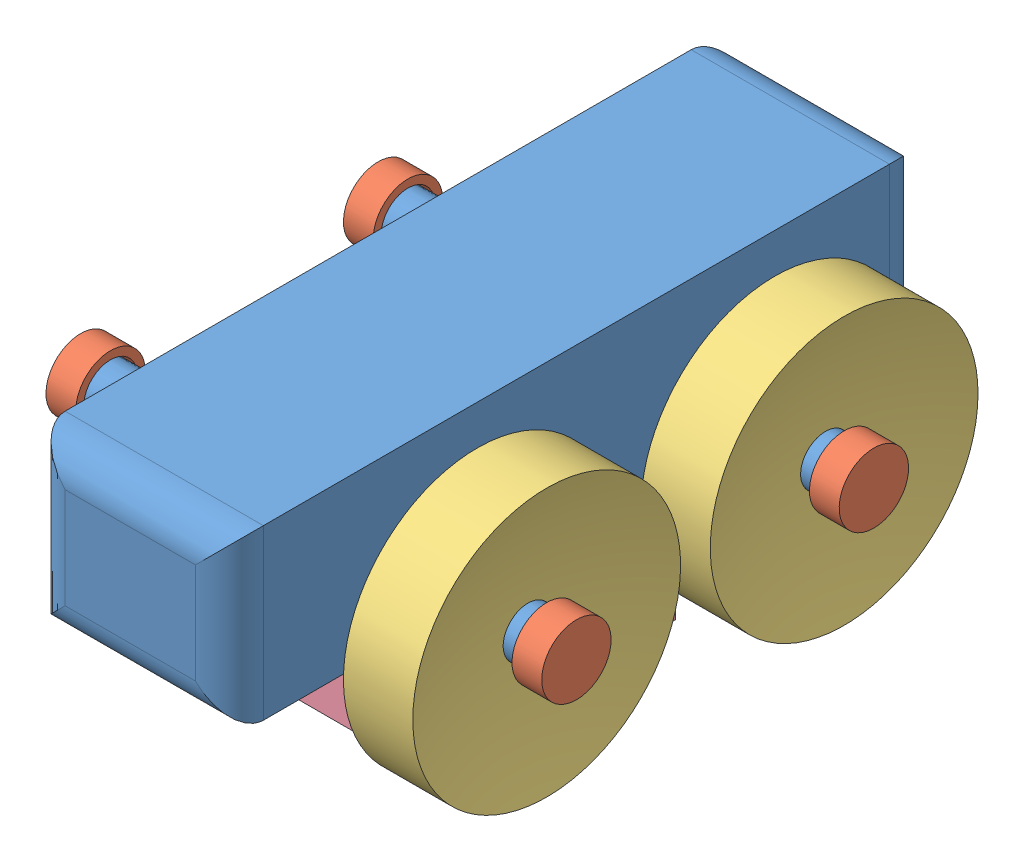
SolidWorks assembly FullCar, configuration Default. Lengths in mm.
Overall size (25 18.99 35).
10 component instances, 4 part files, 11 mates.
Components (placement in the parent):
- Carriage-1: Carriage [Default] at origin size (24.16 8.5 35)
- LockWheels-1: LockWheels [Default] at (12.5 0 7.5) x (0 0.86398 0.503526) z (0 -0.503526 0.86398) size (3.5 7.63 3.5)
- LockWheels-2: LockWheels [Default] at (12.5 0 -7.5) x (0 -0.86398 0.503526) z (0 -0.503526 -0.86398) size (3.5 7.63 3.5)
- LockWheels-3: LockWheels [Default] at (-12.5 0 7.5) x (0 -0.86398 -0.503526) z (0 -0.503526 0.86398) size (3.5 7.63 3.5)
- LockWheels-4: LockWheels [Default] at (-12.5 0 -7.5) x (0 0.86398 -0.503526) z (0 -0.503526 -0.86398) size (3.5 7.63 3.5)
- WheelCarriage-1: WheelCarriage [Default] at (9.25 0 7.5) x (0 -0.862763 -0.505608) z (1 0 0) size (13.5 13.5 3.5)
- WheelCarriage-2: WheelCarriage [Default] at (9.25 0 -7.5) x (0 -0.862763 0.505608) z (-1 0 0) size (13.5 13.5 3.5)
- WheelCarriage-3: WheelCarriage [Default] at (-9.25 0 7.5) x (0 -0.862763 -0.505608) z (1 0 0) size (13.5 13.5 3.5) (hidden)
- WheelCarriage-4: WheelCarriage [Default] at (-9.25 0 -7.5) x (0 -0.862763 0.505608) z (-1 0 0) size (13.5 13.5 3.5) (hidden)
- Support-1: Support [Default] at (0 -7.5 0) x (0 0 1) z (-1 0 0) size (13 7.5 7)
Mates (geometry in assembly coordinates):
- Coincident1: coincident aligned: axis of Carriage-1 through (6.25 0 7.5) axis (1 0 0); line of LockWheels-1 through (5.1 0 7.5) axis (1 0 0)
- Screw1: screw = 1 mm aligned: line of Carriage-1 through (6.25 0 7.5) axis (1 0 0); line of LockWheels-1 through (5.1 0 7.5) axis (1 0 0)
- LimitDistance2: limit distance = 7 mm anti-aligned: plane of Carriage-1 through (5 -1.25 -15.7859) normal (1 0 0); plane of LockWheels-1 through (12 0 7.5) normal (-1 0 0)
- Coincident5: coincident aligned: plane of Carriage-1 through (0 0 0) normal (0 0 1)
- Coincident6: coincident aligned: plane of Carriage-1 through (0 0 0) normal (0 1 0)
- Coincident7: coincident aligned: plane of Carriage-1 through (0 0 0) normal (1 0 0)
- Coincident8: coincident anti-aligned: line of Carriage-1 through (6.25 0 7.5) axis (1 0 0); line of WheelCarriage-1 through (11 0 7.5) axis (-1 0 0)
- LimitDistance3: limit distance = 4.25 mm aligned: plane of Carriage-1 through (5 -1.25 -15.7859) normal (1 0 0); plane of WheelCarriage-1 through (9.25 0 7.5) normal (1 0 0)
- Coincident9: coincident anti-aligned: plane of Carriage-1 through (-3.2859 -2.25 -15.7859) normal (0 -1 0); plane of Support-1 through (0 -2.25 0) normal (0 1 0)
- Coincident10: coincident anti-aligned: plane of Carriage-1 through (0 0 0) normal (1 0 0); plane of Support-1 through (0 -7.5 0) normal (-1 0 0)
- Coincident11: coincident aligned: plane of Carriage-1 through (0 0 0) normal (0 0 1); plane of Support-1 through (0 -7.5 0) normal (0 0 1)
